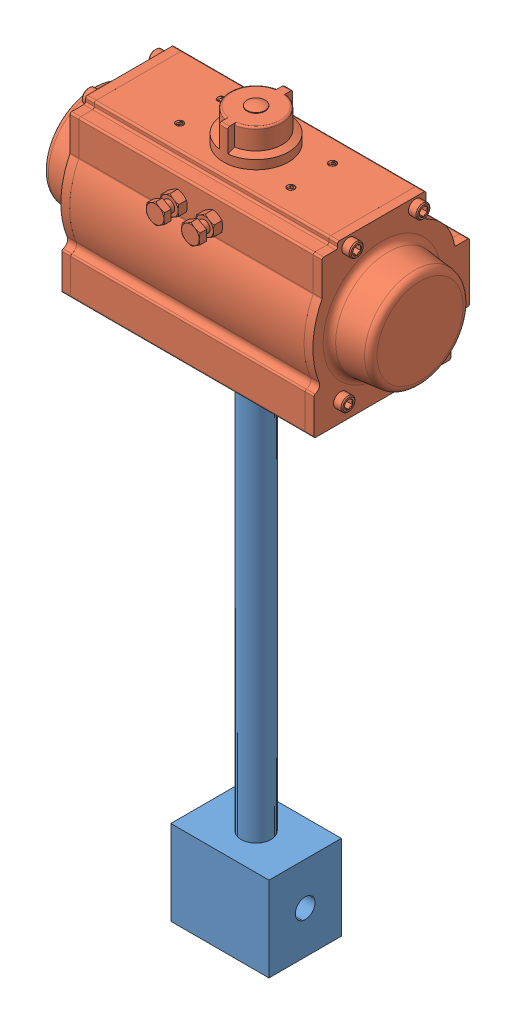
SolidWorks assembly FAKE_SOV-6,7,8, configuration Default. Lengths in mm.
Overall size (235.97 514.41 123.09).
2 component instances, 2 part files, 2 mates.
Components (placement in the parent):
- FAKE_Cryo_SOV_nohandle-1: FAKE_Cryo_SOV_nohandle [Default] at origin size (70.61 381 52.07)
- 49935K880_AIR ACTUATOR FOR BALL-BUTTERFLY VALVE-1: 49935K880_AIR ACTUATOR FOR BALL-BUTTERFLY VALVE [49935K88] at (0 9.525 0) x (0 0 -1) z (1 0 0) size (123.09 139.45 235.97)
Mates (geometry in assembly coordinates):
- Concentric1: concentric anti-aligned: circle of Cryo_HV-1; circle of 49935K880_AIR ACTUATOR FOR BALL-BUTTERFLY VALVE-1
- Parallel1: parallel aligned: plane of Cryo_HV-1 through (-35.306 -365.76 26.035) normal (0 0 1); plane of 49935K880_AIR ACTUATOR FOR BALL-BUTTERFLY VALVE-1 through (90.6462 36.449 49.022) normal (0 0 1)
